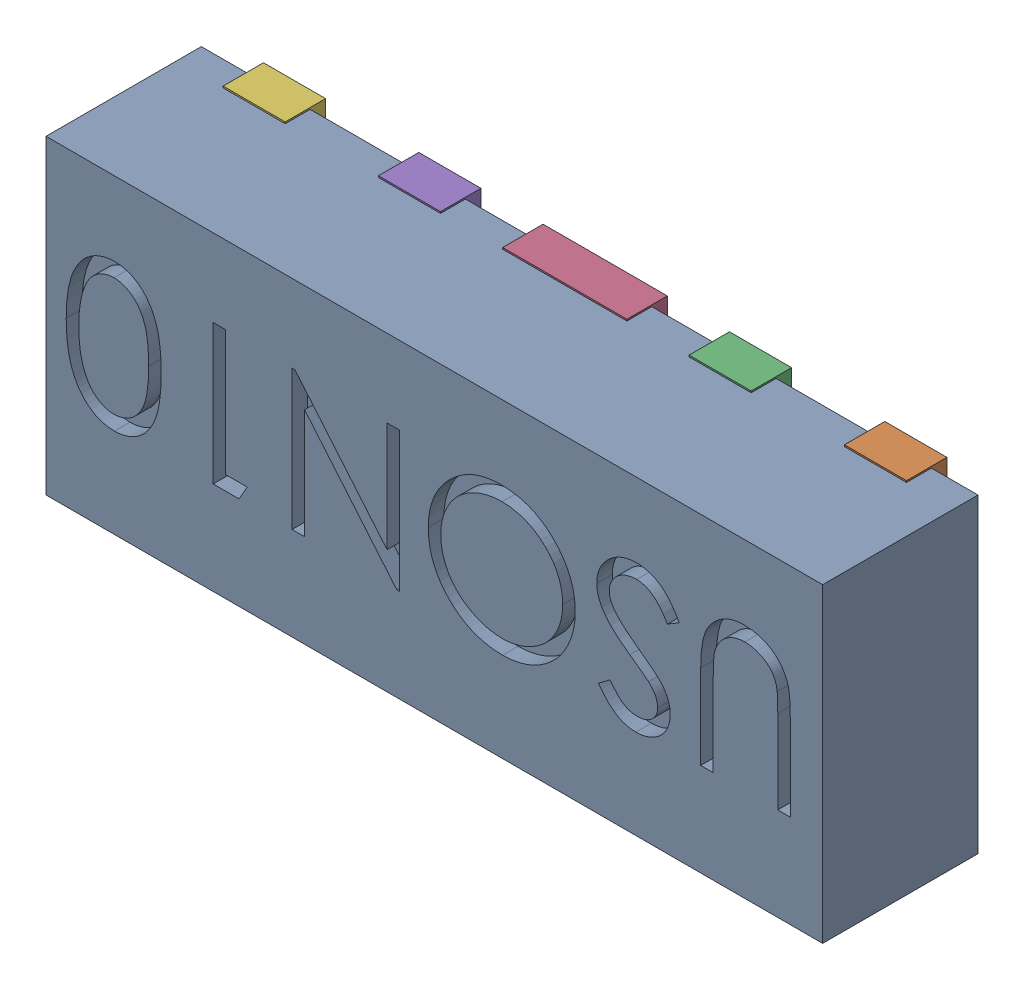
SolidWorks assembly D35, configuration Défaut. Lengths in mm.
Overall size (2.5 1.01 0.55).
12 component instances, 5 part files, 0 mates.
Components (placement in the parent):
- UDFN10-1: UDFN10 [Défaut] at (54.4135 -37.387 -0.9099) x (-1 0 0) z (0 1 0) size (2.5 0.55 1.01)
  - User Library-UDFN10_Body-1: User Library-UDFN10_Body [Défaut] at (1.0785 0.9721 1.8983) size (2.5 0.5 1)
  - User Library-UDFN10_Pin1-1: User Library-UDFN10_Pin1 [Défaut] at (0.0785 1.0521 2.2208) x (0 0 -1) z (-1 0 0) size (0.37 0.13 0.2)
  - User Library-UDFN10_Pin2-1: User Library-UDFN10_Pin2 [Défaut] at (0.5785 1.0521 2.2208) x (0 0 1) z (1 0 0) size (0.37 0.13 0.2)
  - User Library-UDFN10_Pin4-1: User Library-UDFN10_Pin4 [Défaut] at (1.0785 0.9221 2.2208) x (0 0 1) z (-1 0 0) size (0.49 0.13 0.4)
  - User Library-UDFN10_Pin2-2: User Library-UDFN10_Pin2 [Défaut] at (1.5785 0.9221 2.2208) x (0 0 1) z (-1 0 0) size (0.37 0.13 0.2)
  - User Library-UDFN10_Pin2-3: User Library-UDFN10_Pin2 [Défaut] at (2.0785 0.9221 2.2208) x (0 0 1) z (-1 0 0) size (0.37 0.13 0.2)
  - User Library-UDFN10_Pin2-4: User Library-UDFN10_Pin2 [Défaut] at (2.0785 0.9221 1.5758) x (0 0 -1) z (1 0 0) size (0.37 0.13 0.2)
  - User Library-UDFN10_Pin2-5: User Library-UDFN10_Pin2 [Défaut] at (1.5785 0.9221 1.5758) x (0 0 -1) z (1 0 0) size (0.37 0.13 0.2)
  - User Library-UDFN10_Pin3-1: User Library-UDFN10_Pin3 [Défaut] at (1.0785 0.9221 1.5758) x (0 0 1) z (-1 0 0) size (0.37 0.13 0.4)
  - User Library-UDFN10_Pin2-6: User Library-UDFN10_Pin2 [Défaut] at (0.5785 0.9221 1.5758) x (0 0 -1) z (1 0 0) size (0.37 0.13 0.2)
  - User Library-UDFN10_Pin2-7: User Library-UDFN10_Pin2 [Défaut] at (0.0785 0.9221 1.5758) x (0 0 -1) z (1 0 0) size (0.37 0.13 0.2)
